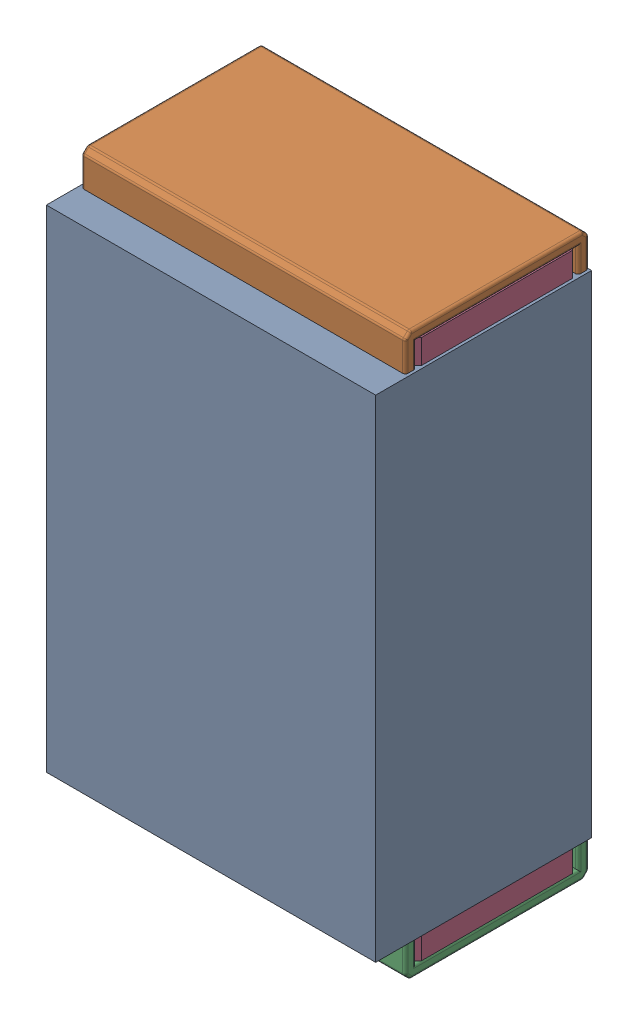
SolidWorks assembly R1, configuration Default. Lengths in mm.
Overall size (0.61 1.04 0.4).
3 component instances, 2 part files, 0 mates.
Components (placement in the parent):
- 1088881848-1: 1088881848 [Default] at (6.15 44.225 0) size (0.61 0.91 0.4)
  - Extruded-1-1: Extruded-1 [Default] at origin size (0.61 0.91 0.4)
- R0402-1: R0402 [Default] at (6.1499 44.225 0) x (0 1 0) z (1 0 0) size (1.04 0.34 0.6)
